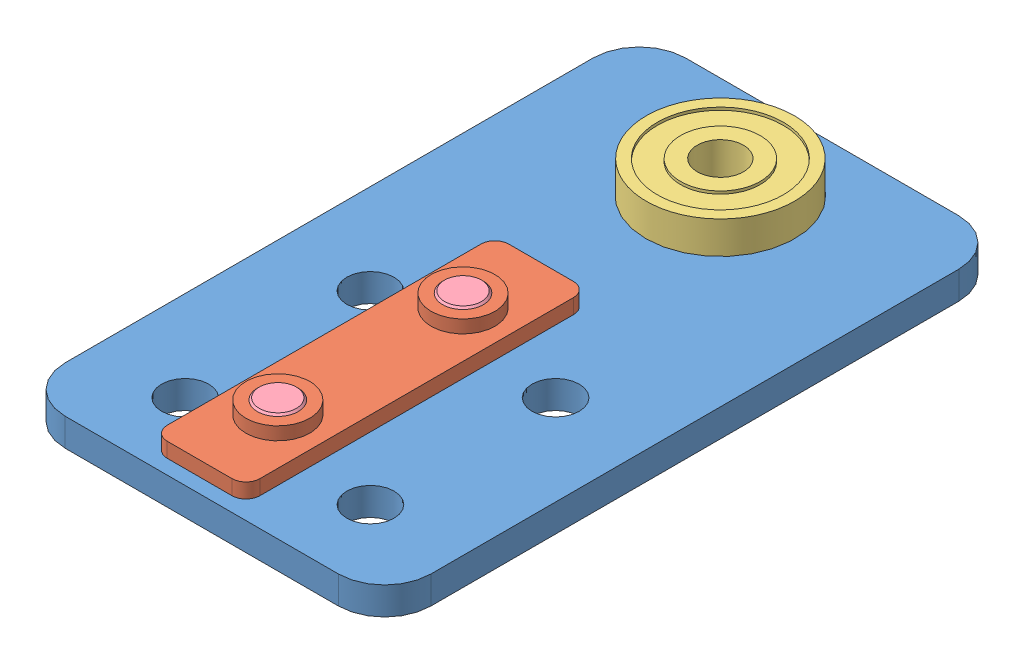
SolidWorks assembly BEARING_MOUNT, configuration Default. Lengths in mm.
Overall size (39.5 9.62 67.23).
5 component instances, 4 part files, 9 mates.
Components (placement in the parent):
- BEARING_PLATE-1: BEARING_PLATE [Default] at (25.0724 29.1129 54.3512) size (39.5 3 67)
- Double Tee Nut-1: Double Tee Nut [Default] at (30.0724 33.9129 88.0812) x (0 0 -1) z (0 1 0) size (36.88 10 3)
- Ball Bearing 5 x 16 x 5-1: Ball Bearing 5 x 16 x 5 [Default] at (25.0724 33.0889 31.8512) x (0 -1 0) z (0 0 1) size (5 16 16)
- LP_SH_SCREW_M5_8mm-1: LP_SH_SCREW_M5_8mm [M5 x 8] at (25.0724 37.1129 59.6412) x (0 1 0) z (0 0 1) size (9.62 9 9)
- LP_SH_SCREW_M5_8mm-2: LP_SH_SCREW_M5_8mm [M5 x 8] at (25.0724 37.1129 79.6412) x (0 1 0) z (0 0 1) size (9.62 9 9)
Mates (geometry in assembly coordinates):
- Width2: width anti-aligned: plane of BEARING_PLATE-1 through (44.8224 32.1129 82.8512) normal (1 0 0); plane of BEARING_PLATE-1 through (5.3224 32.1129 82.8512) normal (-1 0 0); plane of Double Tee Nut-1 through (20.0724 35.5129 86.5812) normal (-1 0 0); plane of Double Tee Nut-1 through (30.0724 35.5129 86.5812) normal (1 0 0)
- Distance2: distance = 1.8 mm anti-aligned: plane of Double Tee Nut-1 through (21.5724 33.9129 52.7012) normal (0 -1 0); plane of BEARING_PLATE-1 through (10.3224 32.1129 82.8512) normal (0 1 0)
- Concentric2: concentric anti-aligned: cylinder of BEARING_PLATE-1 through (25.0724 32.1129 79.6412) axis (0 -1 0) radius 2.55; cylinder of Double Tee Nut-1 through (25.0724 36.9129 79.6412) axis (0 1 0) radius 2.1
- Concentric4: concentric anti-aligned: cylinder of BEARING_PLATE-1 through (25.0724 32.1129 31.8512) axis (0 1 0) radius 8.0518; cylinder of Ball Bearing 5 x 16 x 5-1 through (25.0724 33.0889 31.8512) axis (0 -1 0) radius 8
- Coincident2: coincident anti-aligned: plane of BEARING_PLATE-1 through (29.8349 30.5889 31.8512) normal (0 1 0); plane of Ball Bearing 5 x 16 x 5-1 through (31.8724 30.5889 31.8512) normal (0 -1 0)
- Concentric51: concentric anti-aligned: cylinder of BEARING_PLATE-1 through (25.0724 32.1129 59.6412) axis (0 -1 0) radius 2.55; cylinder of LP_SH_SCREW_M5_8mm-1 through (25.0724 29.1129 59.6412) axis (0 1 0) radius 2.5
- Coincident31: coincident anti-aligned: plane of BEARING_PLATE-1 through (10.3224 29.1129 82.8512) normal (0 -1 0); plane of LP_SH_SCREW_M5_8mm-1 through (20.911 29.1129 59.6412) normal (0 1 0)
- Concentric61: concentric anti-aligned: cylinder of BEARING_PLATE-1 through (25.0724 32.1129 79.6412) axis (0 -1 0) radius 2.55; cylinder of LP_SH_SCREW_M5_8mm-2 through (25.0724 29.1129 79.6412) axis (0 1 0) radius 2.5
- Coincident41: coincident anti-aligned: plane of BEARING_PLATE-1 through (10.3224 29.1129 82.8512) normal (0 -1 0); plane of LP_SH_SCREW_M5_8mm-2 through (20.911 29.1129 79.6412) normal (0 1 0)
